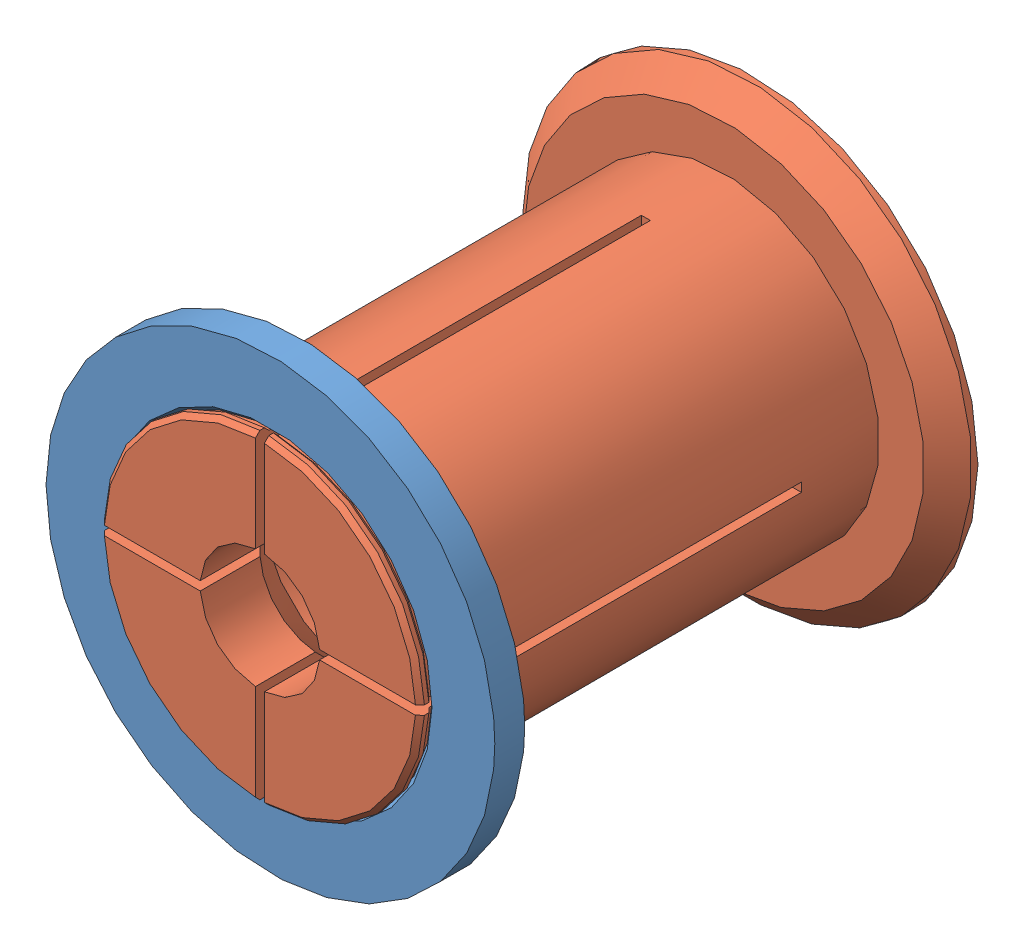
SolidWorks assembly 53-71-20-spool-adapter, configuration Default. Lengths in mm.
Overall size (75 75 82.5).
2 component instances, 2 part files, 2 mates.
Components (placement in the parent):
- 53-71-20-spool-adapter-female-1: 53-71-20-spool-adapter-female [Default] at (17.1616 39.5812 60.4855) size (75 75 5)
- 53-71-20-spool-adapter-male-1: 53-71-20-spool-adapter-male [Default] at (17.1616 39.5812 -10.2645) size (75 75 82.5)
Mates (geometry in assembly coordinates):
- Concentric1: concentric anti-aligned: cylinder of 53-71-20-spool-adapter-female-1 through (17.1616 39.5812 60.4855) axis (0 0 1) radius 26.25; cylinder of 53-71-20-spool-adapter-male-1 through (17.1616 39.5812 67.2355) axis (0 0 -1) radius 26
- Coincident1: coincident aligned: cone of 53-71-20-spool-adapter-female-1 through (17.1616 39.5812 61.2355) axis (0 0 1); cone of 53-71-20-spool-adapter-male-1 through (17.1616 39.5812 61.4855) axis (0 0 1)
